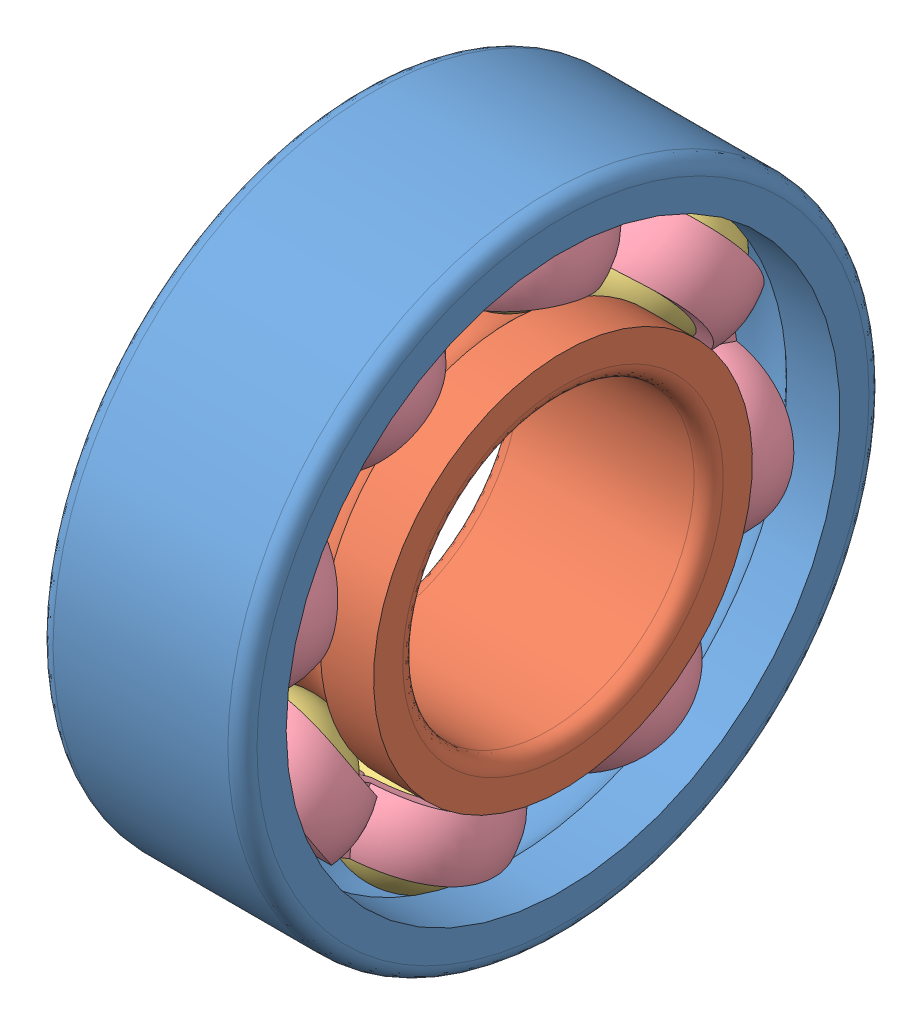
SolidWorks assembly BB_Assembly, configuration Default. Lengths in mm.
Overall size (7 22 22).
12 component instances, 4 part files, 7 mates.
Components (placement in the parent):
- BB_OuterRing-1: BB_OuterRing [Default] at origin size (7 22 22)
- BB_InnerRing-1: BB_InnerRing [Default] x (1 0 0) z (0 0.97954 -0.20125) size (7 13 13)
- BB_Ball-1: BB_Ball [Default] at (0 1.61 7.8363) x (-1 0 0) z (0 -0.97954 0.20125) size (4.5 4.5 4.5)
- BB_Cage-1: BB_Cage [Default] x (0 -0.20125 -0.97954) z (1 0 0) size (18 18 2.77)
- BB_Ball-2: BB_Ball [Default] at (0 6.6796 4.4027) x (-1 0 0) z (0 -0.550334 0.834945) size (4.5 4.5 4.5)
- BB_Ball-3: BB_Ball [Default] at (0 7.8363 -1.61) x (-1 0 0) z (0 0.20125 0.97954) size (4.5 4.5 4.5)
- BB_Ball-4: BB_Ball [Default] at (0 4.4027 -6.6796) x (-1 0 0) z (0 0.834945 0.550334) size (4.5 4.5 4.5)
- BB_Ball-5: BB_Ball [Default] at (0 -1.61 -7.8363) x (-1 0 0) z (0 0.97954 -0.20125) size (4.5 4.5 4.5)
- BB_Ball-6: BB_Ball [Default] at (0 -6.6796 -4.4027) x (-1 0 0) z (0 0.550334 -0.834945) size (4.5 4.5 4.5)
- BB_Ball-7: BB_Ball [Default] at (0 -7.8363 1.61) x (-1 0 0) z (0 -0.20125 -0.97954) size (4.5 4.5 4.5)
- BB_Ball-8: BB_Ball [Default] at (0 -4.4027 6.6796) x (-1 0 0) z (0 -0.834945 -0.550334) size (4.5 4.5 4.5)
- BB_Cage-2: BB_Cage [Default] x (0 0.20125 0.97954) z (-1 0 0) size (18 18 2.77)
Mates (geometry in assembly coordinates):
- Concentric3: concentric aligned: cylinder of BB_OuterRing-1 through (-29.8426 0 0) axis (-1 0 0) radius 11; cylinder of BB_InnerRing-1 through (-42.3909 0 0) axis (-1 0 0) radius 5
- Width1: width anti-aligned: plane of BB_OuterRing-1 through (3.5 9.5 0) normal (1 0 0); plane of BB_InnerRing-1 through (-3.5 9.5 0) normal (-1 0 0); plane of BB_OuterRing-1 through (-3.5 -1.0063 -4.8977) normal (-1 0 0); plane of BB_InnerRing-1 through (3.5 -1.0063 -4.8977) normal (1 0 0)
- Tangent5: tangent anti-aligned: torus of BB_InnerRing-1; sphere of BB_Ball-1
- Coincident8: coincident: line of assembly; axis of BB_InnerRing-1 through (3.7376 0 0) axis (-1 0 0); axis of BB_Cage-1 through (-0.5 0 0) axis (1 0 0)
- Concentric4: concentric: sphere of BB_Cage-1; sphere of BB_Ball-4
- Coincident9: coincident anti-aligned: plane of BB_InnerRing-1 through (0 0 0) normal (1 0 0); plane of BB_Ball-1 through (0 1.61 7.8363) normal (-1 0 0)
- Coincident10: coincident anti-aligned: plane of BB_InnerRing-1 through (0 0 0) normal (0 0.97954 -0.20125); plane of BB_Ball-1 through (0 1.61 7.8363) normal (0 -0.97954 0.20125)
